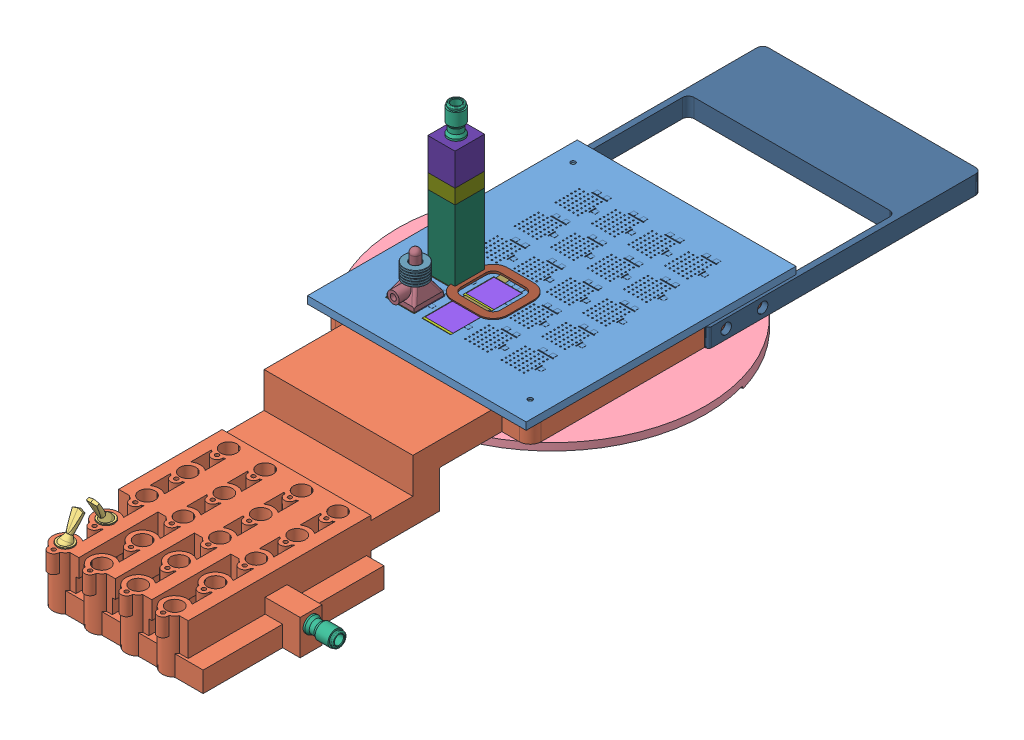
SolidWorks assembly vc probe assembly, configuration Default. Lengths in mm.
Overall size (211.2 190.45 539.55).
47 component instances, 21 part files, 51 mates.
Components (placement in the parent):
- vc probe top-1: vc probe top [Default] at origin size (150 5.1 185)
- vcProbeManifoldV2-1: vcProbeManifoldV2 [new sla post machine] at (0 -61 120) size (145.48 57.6 392.93)
- MTA2NC-1: MTA2NC [Default] at (-37.5 -46.6 296) x (0 -1 0) z (-1 0 0) size (41.72 16.3 11.46)
- MTA2NC-2: MTA2NC [Default] at (-37.5 -46.6 268) x (0 -1 0) z (1 0 0) size (41.72 16.3 11.46)
- vc probe suction plate-1: vc probe suction plate [Default] at (0 -21.4 0) size (211.2 15 211.2)
- one eigth dowel one pt five-1: one eigth dowel one pt five [Default] at (-62.9802 -21.4 -77.6756) size (3.17 25.4 3.17)
- one eigth dowel one pt five-2: one eigth dowel one pt five [Default] at (62.9802 -21.4 77.6756) size (3.17 25.4 3.17)
- Round Head Screw_AI-1: Round Head Screw_AI [PreviewCfg] at (-37.5 -6.5442 304) x (0 -1 0) z (0 0 1) size (77.23 31.75 31.75) (hidden)
- Round Head Screw_AI-2: Round Head Screw_AI [PreviewCfg] at (-37.5 -6.5442 276) x (0 -1 0) z (0 0 1) size (77.23 31.75 31.75) (hidden)
- 5779K140-1: 5779K140 [5779K14] at (79.732 -41.1 240) x (0 -0.990955 0.134191) z (-1 0 0) size (10.92 10.92 29.46)
- chip phase 1-2: chip phase 1 [Default] at (-37.5 5 28) x (0 0 -1) z (1 0 0) size (21.27 0.05 19.67)
  - chip phase 1 frame-1: chip phase 1 frame [Default] at origin size (21.27 0.05 19.67)
  - chip phase 1 active-1: chip phase 1 active [Default] at (0.7464 0 0.1497) size (19.2 0.05 19.2)
  - chip phase 1 pads-2: chip phase 1 pads [Default] at (-10.4848 0 0) size (0.13 0.05 19.3)
- chip phase 1-3: chip phase 1 [Default] at (-12.5 5 28) x (0 0 -1) z (1 0 0) size (21.27 0.05 19.67)
  - chip phase 1 frame-1: chip phase 1 frame [Default] at origin size (21.27 0.05 19.67)
  - chip phase 1 active-1: chip phase 1 active [Default] at (0.7464 0 0.1497) size (19.2 0.05 19.2)
  - chip phase 1 pads-2: chip phase 1 pads [Default] at (-10.4848 0 0) size (0.13 0.05 19.3)
- chip phase 1-4: chip phase 1 [Default] at (-12.5 5 56) x (0 0 -1) z (1 0 0) size (21.27 0.05 19.67)
  - chip phase 1 frame-1: chip phase 1 frame [Default] at origin size (21.27 0.05 19.67)
  - chip phase 1 active-1: chip phase 1 active [Default] at (0.7464 0 0.1497) size (19.2 0.05 19.2)
  - chip phase 1 pads-2: chip phase 1 pads [Default] at (-10.4848 0 0) size (0.13 0.05 19.3)
- chip phase 1-5: chip phase 1 [Default] at (-37.5 5 56) x (0 0 -1) z (1 0 0) size (21.27 0.05 19.67)
  - chip phase 1 frame-1: chip phase 1 frame [Default] at origin size (21.27 0.05 19.67)
  - chip phase 1 active-1: chip phase 1 active [Default] at (0.7464 0 0.1497) size (19.2 0.05 19.2)
  - chip phase 1 pads-2: chip phase 1 pads [Default] at (-10.4848 0 0) size (0.13 0.05 19.3)
- vcCounterWeightV2-1: vcCounterWeightV2 [Default] at (0 -8.2 -0.1756) x (1 0 0) z (0 0 -1) size (150 12.7 187)
- vc_dummy_weight_for_valves-1: vc_dummy_weight_for_valves [Default] at (0 -14.57 240) size (50 13.26 50) (hidden)
- vc_probe_head_asm-1: vc_probe_head_asm [Default] at (-12.1258 6.75 27.9884) size (38 1.7 38)
  - vc_probe_boot-1: vc_probe_boot [Default] at origin size (38 1.5 38)
  - vc_probe_fingers-1: vc_probe_fingers [long] at (0 -1.12 13.6) size (17 0.58 3.2)
  - vc_probe_fingers-2: vc_probe_fingers [short] at (-5.3333 -1.12 -13.6) x (-1 0 0) z (0 0 -1) size (6.33 0.58 3.2)
- vc_pickup_asm-1: vc_pickup_asm [Default] at (-37.5 5.05 56) x (-1 0 0) z (0 0 -1) size (18.67 29.18 25.27)
  - vc_pickup-1: vc_pickup [Default] at origin size (18.67 29.18 25.27)
  - washer 1-4-1: washer 1-4 [Default] at (0 11 0) size (15.88 1.65 15.88)
  - washer 1-4-2: washer 1-4 [Default] at (0 12.651 0) size (15.88 1.65 15.88)
  - washer 1-4-3: washer 1-4 [Default] at (0 14.302 0) size (15.88 1.65 15.88)
  - washer 1-4-4: washer 1-4 [Default] at (0 15.953 0) size (15.88 1.65 15.88)
  - washer 1-4-5: washer 1-4 [Default] at (0 17.604 0) size (15.88 1.65 15.88)
  - washer 1-4-6: washer 1-4 [Default] at (0 19.255 0) size (15.88 1.65 15.88)
- vc_pickup_asm_v2-1: vc_pickup_asm_v2 [Default] at (-37.5 5.05 28) size (18.67 101.46 20.27)
  - vc_pickup_base-1: vc_pickup_base [Default] at origin size (18.67 50 20.27)
  - vc_valve_body-1: vc_valve_body [Default] at (0 55 0) size (18.67 20 20.27)
  - vc_connection-1: vc_connection [Default] at (0 60 0) size (18.67 22 20.27)
  - 5779K140-1: 5779K140 [5779K14] at (0 86.732 0) x (0.965257 0 -0.261301) z (0 1 0) size (10.92 10.92 29.46)
  - vc_valve_flap-1: vc_valve_flap [Default] at (0 65 0) size (15.5 0.05 17)
  - vc_staple-1: vc_staple [Default] at (0 65 0) x (0 0 1) z (-1 0 0) size (12.7 6.25 0.5)
Mates (geometry in assembly coordinates):
- Coincident1: coordinate: point of vc probe top-1; point of assembly
- Coincident3: coincident aligned: plane of vc probe top-1 through (-75 5 -92.5) normal (0 0 -1); plane of vcProbeManifoldV2-1 through (-75 4 -92.5) normal (0 0 -1)
- Coincident4: coincident aligned: plane of vc probe top-1 through (75 5 -92.5) normal (1 0 0); plane of vcProbeManifoldV2-1 through (75 4 -92.5) normal (1 0 0)
- Concentric1: concentric aligned: cylinder of MTA2NC-1 through (-37.5 -43.8695 296) axis (0 1 0) radius 5.5118; cylinder of vcProbeManifoldV2-1 through (-37.5 -62.2978 296) axis (0 1 0) radius 5.55
- Coincident5: coincident anti-aligned: plane of vcProbeManifoldV2-1 through (-37.5 -46.6 296) normal (0 1 0); plane of MTA2NC-1 through (-34.2998 -46.6 294.1523) normal (0 -1 0)
- Parallel1: parallel anti-aligned: plane of MTA2NC-1 through (-37.5 -46.6 296) normal (-1 0 0); plane of assembly through (0 0 0) normal (1 0 0)
- Concentric2: concentric aligned: cylinder of MTA2NC-2 through (-37.5 -43.8695 268) axis (0 1 0) radius 5.5118; cylinder of vcProbeManifoldV2-1 through (-37.5 -62.2978 268) axis (0 1 0) radius 5.55
- Coincident7: coincident anti-aligned: plane of vcProbeManifoldV2-1 through (-37.5 -46.6 268) normal (0 1 0); plane of MTA2NC-2 through (-40.7002 -46.6 269.8477) normal (0 -1 0)
- Parallel2: parallel aligned: plane of MTA2NC-2 through (-37.5 -46.6 268) normal (1 0 0); plane of assembly through (0 0 0) normal (1 0 0)
- Coincident9: coincident aligned: plane of vc probe suction plate-1 through (0 -21.4 0) normal (0 0 1); plane of assembly through (0 0 0) normal (0 0 1)
- Coincident10: coincident aligned: plane of vc probe suction plate-1 through (0 -21.4 0) normal (1 0 0); plane of assembly through (0 0 0) normal (1 0 0)
- Coincident11: coincident anti-aligned: plane of vc probe top-1 through (-75 0 92.5) normal (0 -1 0); plane of vcProbeManifoldV2-1 through (-75 0 87.6756) normal (0 1 0)
- Coincident12: coincident anti-aligned: plane of vc probe suction plate-1 through (0 -16.4 0) normal (0 1 0); plane of vcProbeManifoldV2-1 through (-62.9802 -16.4 77.6756) normal (0 -1 0)
- Coincident13: coincident anti-aligned: circle of vc probe top-1; cylinder of one eigth dowel one pt five-1 through (-62.9802 4 -77.6756) axis (0 -1 0) radius 1.5875
- Concentric3: concentric anti-aligned: cylinder of vc probe top-1 through (62.9802 0 77.6756) axis (0 1 0) radius 1.5875; cylinder of one eigth dowel one pt five-2 through (62.9802 4 77.6756) axis (0 -1 0) radius 1.5875
- Coincident14: coincident aligned: plane of vc probe suction plate-1 through (0 -21.4 0) normal (0 -1 0); plane of one eigth dowel one pt five-2 through (62.9802 -21.4 77.6756) normal (0 -1 0)
- Coincident15: coincident aligned: plane of vc probe suction plate-1 through (0 -21.4 0) normal (0 -1 0); plane of one eigth dowel one pt five-1 through (-62.9802 -21.4 -77.6756) normal (0 -1 0)
- Coincident16: coincident anti-aligned: plane of Round Head Screw_AI-1 through (-27.975 -20.438 304) normal (0 -1 0); plane of MTA2NC-1 through (-35.1738 -20.438 294.657) normal (0 1 0)
- Concentric4: concentric aligned: cylinder of vcProbeManifoldV2-1 through (-37.5 -21.2 304) axis (0 1 0) radius 1.3526; cylinder of Round Head Screw_AI-1 through (-37.5 -6.5442 304) axis (0 1 0) radius 9.525
- Coincident17: coincident anti-aligned: plane of MTA2NC-2 through (-39.8262 -20.438 269.343) normal (0 1 0); plane of Round Head Screw_AI-2 through (-27.975 -20.438 276) normal (0 -1 0)
- Concentric5: concentric aligned: circle of vcProbeManifoldV2-1; cylinder of Round Head Screw_AI-2 through (-37.5 -6.5442 276) axis (0 1 0) radius 9.525
- Concentric6: concentric aligned: cylinder of 5779K140-1 through (79.732 -41.1 240) axis (1 0 0) radius 5.461; cylinder of vcProbeManifoldV2-1 through (65 -41.1 240) axis (1 0 0) radius 5.5
- Coincident18: coincident anti-aligned: plane of vcProbeManifoldV2-1 through (65 -41.1 240) normal (1 0 0); plane of 5779K140-1 through (65 -40.5427 244.1153) normal (-1 0 0)
- Coincident19: coincident anti-aligned: plane of vc probe top-1 through (-27.665 5.1 29.5) normal (-1 0 0); plane of chip phase 1-2/chip phase 1 frame-1 through (-27.665 5.05 38.635) normal (1 0 0)
- Coincident20: coincident anti-aligned: plane of vc probe top-1 through (-28.665 5.1 17.365) normal (0 0 1); plane of chip phase 1-2/chip phase 1 frame-1 through (-47.335 5.05 17.365) normal (0 0 -1)
- Coincident21: coincident anti-aligned: plane of vc probe top-1 through (-75 5 92.5) normal (0 1 0); plane of chip phase 1-2/chip phase 1 active-1 through (-27.7503 5 36.8535) normal (0 -1 0)
- Coincident22: coincident anti-aligned: plane of vc probe top-1 through (-2.665 5.1 29.5) normal (-1 0 0); plane of chip phase 1-3/chip phase 1 frame-1 through (-2.665 5.05 38.635) normal (1 0 0)
- Coincident23: coincident anti-aligned: plane of vc probe top-1 through (-3.665 5.1 17.365) normal (0 0 1); plane of chip phase 1-3/chip phase 1 frame-1 through (-22.335 5.05 17.365) normal (0 0 -1)
- Coincident24: coincident anti-aligned: plane of vc probe top-1 through (-75 5 92.5) normal (0 1 0); plane of chip phase 1-3/chip phase 1 active-1 through (-2.7503 5 36.8535) normal (0 -1 0)
- Coincident25: coincident anti-aligned: plane of vc probe top-1 through (-27.665 5.1 57.5) normal (-1 0 0); plane of chip phase 1-5/chip phase 1 frame-1 through (-27.665 5.05 66.635) normal (1 0 0)
- Coincident26: coincident anti-aligned: plane of vc probe top-1 through (-28.665 5.1 45.365) normal (0 0 1); plane of chip phase 1-5/chip phase 1 frame-1 through (-47.335 5.05 45.365) normal (0 0 -1)
- Coincident27: coincident anti-aligned: plane of vc probe top-1 through (-75 5 92.5) normal (0 1 0); plane of chip phase 1-5/chip phase 1 active-1 through (-27.7503 5 64.8535) normal (0 -1 0)
- Coincident28: coincident anti-aligned: plane of vc probe top-1 through (-3.665 5.1 45.365) normal (0 0 1); plane of chip phase 1-4/chip phase 1 frame-1 through (-22.335 5.05 45.365) normal (0 0 -1)
- Coincident29: coincident anti-aligned: plane of vc probe top-1 through (-2.665 5.1 57.5) normal (-1 0 0); plane of chip phase 1-4/chip phase 1 frame-1 through (-2.665 5.05 66.635) normal (1 0 0)
- Coincident30: coincident anti-aligned: plane of vc probe top-1 through (-75 5 92.5) normal (0 1 0); plane of chip phase 1-4/chip phase 1 active-1 through (-2.7503 5 64.8535) normal (0 -1 0)
- Coincident31: coincident aligned: plane of vcCounterWeightV2-1; plane of assembly through (0 0 0) normal (1 0 0)
- Concentric7: concentric aligned: cylinder of vcCounterWeightV2-1 through (75 -8.2 -44.6756) axis (1 0 0) radius 3.5712; cylinder of vcProbeManifoldV2-1 through (70.4802 -8.2 -44.6756) axis (1 0 0) radius 2.5527
- Concentric8: concentric aligned: cylinder of vcCounterWeightV2-1 through (75 -8.2 -69.6756) axis (1 0 0) radius 3.5712; cylinder of vcProbeManifoldV2-1 through (70.4802 -8.2 -69.6756) axis (1 0 0) radius 2.5527
- Concentric9: concentric anti-aligned: cylinder of one eigth dowel one pt five-2 through (62.9802 4 77.6756) axis (0 -1 0) radius 1.5875; cylinder of vcProbeManifoldV2-1 through (62.9802 -57.6001 77.6756) axis (0 1 0) radius 1.5875
- Coincident32: coincident anti-aligned: plane of vcProbeManifoldV2-1 through (-75 -21.2 332.5) normal (0 1 0); plane of vc_dummy_weight_for_valves-1 through (-25 -21.2 265) normal (0 -1 0)
- Symmetric1: symmetric aligned: plane of vcProbeManifoldV2-1 through (-51 -61 308) normal (-1 0 0); plane of vcProbeManifoldV2-1 through (51 -61 87.6756) normal (1 0 0); plane of vc_dummy_weight_for_valves-1 through (0 -14.57 240) normal (1 0 0)
- Symmetric2: symmetric aligned: plane of vcProbeManifoldV2-1 through (75 -61 247.5) normal (0 0 1); plane of vcProbeManifoldV2-1 through (63 -61 232.5) normal (0 0 -1); plane of vc_dummy_weight_for_valves-1 through (0 -14.57 240) normal (0 0 1)
- Parallel3: parallel aligned: plane of vc_probe_head_asm-1/vc_probe_boot-1 through (-12.1258 6.75 27.9884) normal (0 1 0); plane of assembly through (0 0 0) normal (0 1 0)
- Parallel4: parallel aligned: plane of vc_probe_head_asm-1/vc_probe_boot-1 through (-12.1258 6.75 27.9884) normal (1 0 0); plane of assembly through (0 0 0) normal (1 0 0)
- Coincident33: coincident aligned: plane of chip phase 1-2/chip phase 1 active-1 through (-27.7503 5.05 36.8535) normal (0 1 0); plane of vc_probe_head_asm-1/vc_probe_fingers-1 through (-12.1258 5.05 41.5884) normal (0 1 0)
- Symmetric3: symmetric aligned: plane of chip phase 1-5/chip phase 1 frame-1 through (-27.665 5.05 66.635) normal (1 0 0); plane of chip phase 1-5/chip phase 1 frame-1 through (-47.335 5.05 66.635) normal (-1 0 0); plane of vc_pickup_asm-1/vc_pickup-1 through (-37.5 5.05 56) normal (-1 0 0)
- Coincident34: coincident anti-aligned: plane of chip phase 1-5/chip phase 1 active-1 through (-27.7503 5.05 64.8535) normal (0 1 0); plane of vc_pickup_asm-1/vc_pickup-1 through (-28.165 5.05 45.865) normal (0 -1 0)
- Symmetric4: symmetric aligned: plane of chip phase 1-5/chip phase 1 frame-1 through (-47.335 5.05 45.365) normal (0 0 -1); plane of chip phase 1-5/chip phase 1 frame-1 through (-47.335 5.05 66.635) normal (0 0 1); plane of vc_pickup_asm-1/vc_pickup-1 through (-37.5 5.05 56) normal (0 0 -1)
- Symmetric5: symmetric aligned: plane of chip phase 1-2/chip phase 1 frame-1 through (-27.665 5.05 38.635) normal (1 0 0); plane of chip phase 1-2/chip phase 1 frame-1 through (-47.335 5.05 38.635) normal (-1 0 0); plane of vc_pickup_asm_v2-1/vc_pickup_base-1 through (-37.5 5.05 28) normal (1 0 0)
- Symmetric6: symmetric aligned: plane of chip phase 1-2/chip phase 1 frame-1 through (-47.335 5.05 38.635) normal (0 0 1); plane of chip phase 1-2/chip phase 1 frame-1 through (-47.335 5.05 17.365) normal (0 0 -1); plane of vc_pickup_asm_v2-1/vc_pickup_base-1 through (-37.5 5.05 28) normal (0 0 1)
- Coincident35: coincident anti-aligned: plane of chip phase 1-2/chip phase 1 active-1 through (-27.7503 5.05 36.8535) normal (0 1 0); plane of vc_pickup_asm_v2-1/vc_pickup_base-1 through (-46.835 5.05 38.135) normal (0 -1 0)
